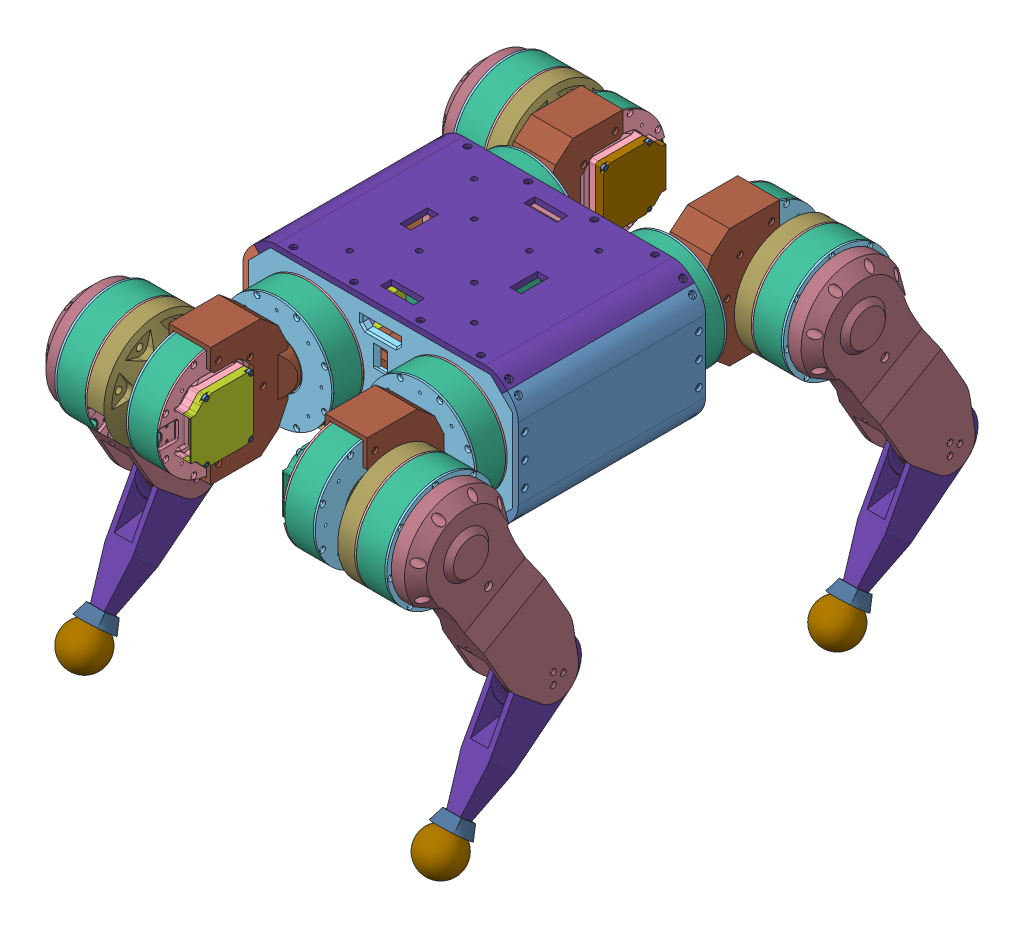
SolidWorks assembly mk2 chassis, configuration Default. Lengths in mm.
Overall size (361.4 327.83 552.81).
210 component instances, 45 part files, 0 mates.
Components (placement in the parent):
- mk2 chassis.stp-1: mk2 chassis.stp [Default] at origin size (361.4 327.83 552.81)
  - mk2 leg.stp-1: mk2 leg.stp [Default] at (-65 0 95) size (165.7 327.83 192.81)
    - qdd100 external.stp-1: qdd100 external.stp [Default] x (0 1 0) z (0 0 1) size (100 100 44.2)
      - Back Cover.stp-1: Back Cover.stp [Default] at origin size (56.5 56.9 10.6)
        - 91292A012.stp-1: 91292A012.stp [Default] at (-26 19 -14.4) size (4.5 4.5 10.5)
        - 91292A012.stp-2: 91292A012.stp [Default] at (26 19 -14.4) size (4.5 4.5 10.5)
        - 91292A012.stp-3: 91292A012.stp [Default] at (26 -21 -14.4) size (4.5 4.5 10.5)
        - 91292A012.stp-4: 91292A012.stp [Default] at (-26 -21 -14.4) size (4.5 4.5 10.5)
        - Back Cover-0.stp-1: Back Cover-0.stp [Default] at origin size (56.5 56.9 7.5)
      - Planet Output.stp-1: Planet Output.stp [Default] at (0 0 12.2) x (0.5 -0.866025 0) z (0 0 1) size (43 43 14.5)
      - Back Housing.stp-1: Back Housing.stp [Default] at (0 0 -1.5) size (100 99.47 11)
      - Front Housing.stp-1: Front Housing.stp [Default] at (0 0 12.2) size (100 100 20.87)
      - Outer Housing.stp-1: Outer Housing.stp [Default] at origin size (100 100 25.8)
    - qdd100 external_1.stp-1: qdd100 external_1.stp [Default] at (-1.5 0 85) x (0 1 0) z (-1 0 0) size (100 100 44.2)
      - Back Cover_1.stp-1: Back Cover_1.stp [Default] at origin size (56.5 56.9 10.6)
        - 91292A012.stp-1: 91292A012.stp [Default] at (-26 19 -14.4) size (4.5 4.5 10.5)
        - 91292A012.stp-2: 91292A012.stp [Default] at (26 19 -14.4) size (4.5 4.5 10.5)
        - 91292A012.stp-3: 91292A012.stp [Default] at (26 -21 -14.4) size (4.5 4.5 10.5)
        - 91292A012.stp-4: 91292A012.stp [Default] at (-26 -21 -14.4) size (4.5 4.5 10.5)
        - Back Cover_1-1.stp-1: Back Cover_1-1.stp [Default] at origin size (56.5 56.9 7.5)
      - Planet Output.stp-1: Planet Output.stp [Default] at (0 0 12.2) size (43 43 14.5)
      - Back Housing.stp-1: Back Housing.stp [Default] at (0 0 -1.5) size (100 99.47 11)
      - Front Housing.stp-1: Front Housing.stp [Default] at (0 0 12.2) size (100 100 20.87)
      - Outer Housing.stp-1: Outer Housing.stp [Default] at origin size (100 100 25.8)
    - qdd100 external_2.stp-1: qdd100 external_2.stp [Default] at (-66.5 0 85) x (0 0.866025 0.5) z (-1 0 0) size (100 100 44.2)
      - Back Cover_2.stp-1: Back Cover_2.stp [Default] at origin size (56.5 56.9 10.6)
        - 91292A012.stp-1: 91292A012.stp [Default] at (-26 19 -14.4) size (4.5 4.5 10.5)
        - 91292A012.stp-2: 91292A012.stp [Default] at (26 19 -14.4) size (4.5 4.5 10.5)
        - 91292A012.stp-3: 91292A012.stp [Default] at (26 -21 -14.4) size (4.5 4.5 10.5)
        - 91292A012.stp-4: 91292A012.stp [Default] at (-26 -21 -14.4) size (4.5 4.5 10.5)
        - Back Cover_2-2.stp-1: Back Cover_2-2.stp [Default] at origin size (56.5 56.9 7.5)
      - Planet Output.stp-1: Planet Output.stp [Default] at (0 0 12.2) size (43 43 14.5)
      - Back Housing.stp-1: Back Housing.stp [Default] at (0 0 -1.5) size (100 99.47 11)
      - Front Housing.stp-1: Front Housing.stp [Default] at (0 0 12.2) size (100 100 20.87)
      - Outer Housing.stp-1: Outer Housing.stp [Default] at origin size (100 100 25.8)
    - Leg.stp-1: Leg.stp [Default] at origin size (137.7 327.83 192.56)
      - Foot.stp-1: Foot.stp [Default] at (0 -69.5691 -150.7891) x (1 0 0) z (0 0.642788 0.766044) size (38 45.01 38)
        - Ball.stp-1: Ball.stp [Default] at (0 -369.35 -177) x (1 0 0) z (0 1 0) size (38 38 38)
        - Foot Bracket.stp-1: Foot Bracket.stp [Default] at origin size (32.62 31.01 32.62)
      - Shoulder.stp-1: Shoulder.stp [Default] at origin size (47 108 73)
      - Upper Motor Joint.stp-1: Upper Motor Joint.stp [Default] at (0 42.5 11.3878) x (1 0 0) z (0 -0.5 0.866025) size (35.8 100 99.71)
      - Upper Leg.stp-1: Upper Leg.stp [Default] at (0 42.5 11.3878) x (1 0 0) z (0 -0.5 0.866025) size (37 215.35 92)
      - Tensioner.stp-1: Tensioner.stp [Default] at (-96.7 -77.8341 57.383) x (1 0 0) z (0 -0.5 0.866025) size (27 10 16)
      - Upper Pulley.stp-1: Upper Pulley.stp [Default] at (0 42.5 11.3878) x (1 0 0) z (0 -0.5 0.866025) size (20.2 27.85 27.54)
      - Upper Pulley Adapter.stp-1: Upper Pulley Adapter.stp [Default] at (0 42.5 11.3878) x (1 0 0) z (0 -0.5 0.866025) size (3 43 43)
      - Lower Leg.stp-1: Lower Leg.stp [Default] at (0 -69.5691 -150.7891) x (1 0 0) z (0 0.642788 0.766044) size (25.02 152.46 56.93)
      - Lower Pulley.stp-1: Lower Pulley.stp [Default] at (0 42.5 11.3878) x (1 0 0) z (0 -0.5 0.866025) size (16 50.03 50.03)
      - Knee Stud.stp-1: Knee Stud.stp [Default] at (0 42.5 11.3878) x (1 0 0) z (0 -0.5 0.866025) size (25 20 20)
  - mk2 leg_1.stp-1: mk2 leg_1.stp [Default] at (65 0 -95) x (-1 0 0) z (0 0 -1) size (165.7 327.83 234.51)
    - qdd100 external_3.stp-1: qdd100 external_3.stp [Default] x (0 1 0) z (0 0 1) size (100 100 44.2)
      - Back Cover_3.stp-1: Back Cover_3.stp [Default] at origin size (56.5 56.9 10.6)
        - 91292A012.stp-1: 91292A012.stp [Default] at (-26 19 -14.4) size (4.5 4.5 10.5)
        - 91292A012.stp-2: 91292A012.stp [Default] at (26 19 -14.4) size (4.5 4.5 10.5)
        - 91292A012.stp-3: 91292A012.stp [Default] at (26 -21 -14.4) size (4.5 4.5 10.5)
        - 91292A012.stp-4: 91292A012.stp [Default] at (-26 -21 -14.4) size (4.5 4.5 10.5)
        - Back Cover_3-3.stp-1: Back Cover_3-3.stp [Default] at origin size (56.5 56.9 7.5)
      - Planet Output.stp-1: Planet Output.stp [Default] at (0 0 12.2) x (0.5 -0.866025 0) z (0 0 1) size (43 43 14.5)
      - Back Housing.stp-1: Back Housing.stp [Default] at (0 0 -1.5) size (100 99.47 11)
      - Front Housing.stp-1: Front Housing.stp [Default] at (0 0 12.2) size (100 100 20.87)
      - Outer Housing.stp-1: Outer Housing.stp [Default] at origin size (100 100 25.8)
    - qdd100 external_4.stp-1: qdd100 external_4.stp [Default] at (-1.5 0 85) x (0 1 0) z (-1 0 0) size (100 100 44.2)
      - Back Cover_4.stp-1: Back Cover_4.stp [Default] at origin size (56.5 56.9 10.6)
        - 91292A012.stp-1: 91292A012.stp [Default] at (-26 19 -14.4) size (4.5 4.5 10.5)
        - 91292A012.stp-2: 91292A012.stp [Default] at (26 19 -14.4) size (4.5 4.5 10.5)
        - 91292A012.stp-3: 91292A012.stp [Default] at (26 -21 -14.4) size (4.5 4.5 10.5)
        - 91292A012.stp-4: 91292A012.stp [Default] at (-26 -21 -14.4) size (4.5 4.5 10.5)
        - Back Cover_4-4.stp-1: Back Cover_4-4.stp [Default] at origin size (56.5 56.9 7.5)
      - Planet Output.stp-1: Planet Output.stp [Default] at (0 0 12.2) size (43 43 14.5)
      - Back Housing.stp-1: Back Housing.stp [Default] at (0 0 -1.5) size (100 99.47 11)
      - Front Housing.stp-1: Front Housing.stp [Default] at (0 0 12.2) size (100 100 20.87)
      - Outer Housing.stp-1: Outer Housing.stp [Default] at origin size (100 100 25.8)
    - qdd100 external_5.stp-1: qdd100 external_5.stp [Default] at (-66.5 0 85) x (0 0.866025 -0.5) z (-1 0 0) size (100 100 44.2)
      - Back Cover_5.stp-1: Back Cover_5.stp [Default] at origin size (56.5 56.9 10.6)
        - 91292A012.stp-1: 91292A012.stp [Default] at (-26 19 -14.4) size (4.5 4.5 10.5)
        - 91292A012.stp-2: 91292A012.stp [Default] at (26 19 -14.4) size (4.5 4.5 10.5)
        - 91292A012.stp-3: 91292A012.stp [Default] at (26 -21 -14.4) size (4.5 4.5 10.5)
        - 91292A012.stp-4: 91292A012.stp [Default] at (-26 -21 -14.4) size (4.5 4.5 10.5)
        - Back Cover_5-5.stp-1: Back Cover_5-5.stp [Default] at origin size (56.5 56.9 7.5)
      - Planet Output.stp-1: Planet Output.stp [Default] at (0 0 12.2) size (43 43 14.5)
      - Back Housing.stp-1: Back Housing.stp [Default] at (0 0 -1.5) size (100 99.47 11)
      - Front Housing.stp-1: Front Housing.stp [Default] at (0 0 12.2) size (100 100 20.87)
      - Outer Housing.stp-1: Outer Housing.stp [Default] at origin size (100 100 25.8)
    - Leg_1.stp-1: Leg_1.stp [Default] at origin size (137.7 327.68 192.81)
      - Foot_1.stp-1: Foot_1.stp [Default] at (0 39.7048 190.5616) x (1 0 0) z (0 -0.642788 0.766044) size (38 45.01 38)
        - Ball.stp-1: Ball.stp [Default] at (0 -369.35 -177) x (1 0 0) z (0 1 0) size (38 38 38)
        - Foot Bracket.stp-1: Foot Bracket.stp [Default] at origin size (32.62 31.01 32.62)
      - Shoulder.stp-1: Shoulder.stp [Default] at origin size (47 108 73)
      - Upper Motor Joint.stp-1: Upper Motor Joint.stp [Default] at (0 -42.5 11.3878) x (1 0 0) z (0 0.5 0.866025) size (35.8 100 99.71)
      - Upper Leg.stp-1: Upper Leg.stp [Default] at (0 -42.5 11.3878) x (1 0 0) z (0 0.5 0.866025) size (37 215.35 92)
      - Tensioner.stp-1: Tensioner.stp [Default] at (-96.7 -62.8341 138.5978) x (1 0 0) z (0 0.5 0.866025) size (27 10 16)
      - Upper Pulley.stp-1: Upper Pulley.stp [Default] at (0 -42.5 11.3878) x (1 0 0) z (0 0.5 0.866025) size (20.2 27.85 27.54)
      - Upper Pulley Adapter.stp-1: Upper Pulley Adapter.stp [Default] at (0 -42.5 11.3878) x (1 0 0) z (0 0.5 0.866025) size (3 43 43)
      - Lower Leg.stp-1: Lower Leg.stp [Default] at (0 39.7048 190.5616) x (1 0 0) z (0 -0.642788 0.766044) size (25.02 152.46 56.93)
      - Lower Pulley.stp-1: Lower Pulley.stp [Default] at (0 -42.5 11.3878) x (1 0 0) z (0 0.5 0.866025) size (16 50.03 50.03)
      - Knee Stud.stp-1: Knee Stud.stp [Default] at (0 -42.5 11.3878) x (1 0 0) z (0 0.5 0.866025) size (25 20 20)
  - mk2 leg_2.stp-1: mk2 leg_2.stp [Default] at (65 0 95) x (-1 0 0) z (0 0 1) size (165.7 327.83 192.81)
    - qdd100 external_6.stp-1: qdd100 external_6.stp [Default] x (0 1 0) z (0 0 1) size (100 100 44.2)
      - Back Cover_6.stp-1: Back Cover_6.stp [Default] at origin size (56.5 56.9 10.6)
        - 91292A012.stp-1: 91292A012.stp [Default] at (-26 19 -14.4) size (4.5 4.5 10.5)
        - 91292A012.stp-2: 91292A012.stp [Default] at (26 19 -14.4) size (4.5 4.5 10.5)
        - 91292A012.stp-3: 91292A012.stp [Default] at (26 -21 -14.4) size (4.5 4.5 10.5)
        - 91292A012.stp-4: 91292A012.stp [Default] at (-26 -21 -14.4) size (4.5 4.5 10.5)
        - Back Cover_6-6.stp-1: Back Cover_6-6.stp [Default] at origin size (56.5 56.9 7.5)
      - Planet Output.stp-1: Planet Output.stp [Default] at (0 0 12.2) x (0.5 -0.866025 0) z (0 0 1) size (43 43 14.5)
      - Back Housing.stp-1: Back Housing.stp [Default] at (0 0 -1.5) size (100 99.47 11)
      - Front Housing.stp-1: Front Housing.stp [Default] at (0 0 12.2) size (100 100 20.87)
      - Outer Housing.stp-1: Outer Housing.stp [Default] at origin size (100 100 25.8)
    - qdd100 external_7.stp-1: qdd100 external_7.stp [Default] at (-1.5 0 85) x (0 1 0) z (-1 0 0) size (100 100 44.2)
      - Back Cover_7.stp-1: Back Cover_7.stp [Default] at origin size (56.5 56.9 10.6)
        - 91292A012.stp-1: 91292A012.stp [Default] at (-26 19 -14.4) size (4.5 4.5 10.5)
        - 91292A012.stp-2: 91292A012.stp [Default] at (26 19 -14.4) size (4.5 4.5 10.5)
        - 91292A012.stp-3: 91292A012.stp [Default] at (26 -21 -14.4) size (4.5 4.5 10.5)
        - 91292A012.stp-4: 91292A012.stp [Default] at (-26 -21 -14.4) size (4.5 4.5 10.5)
        - Back Cover_7-7.stp-1: Back Cover_7-7.stp [Default] at origin size (56.5 56.9 7.5)
      - Planet Output.stp-1: Planet Output.stp [Default] at (0 0 12.2) size (43 43 14.5)
      - Back Housing.stp-1: Back Housing.stp [Default] at (0 0 -1.5) size (100 99.47 11)
      - Front Housing.stp-1: Front Housing.stp [Default] at (0 0 12.2) size (100 100 20.87)
      - Outer Housing.stp-1: Outer Housing.stp [Default] at origin size (100 100 25.8)
    - qdd100 external_8.stp-1: qdd100 external_8.stp [Default] at (-66.5 0 85) x (0 -0.866025 0.5) z (-1 0 0) size (100 100 44.2)
      - Back Cover_8.stp-1: Back Cover_8.stp [Default] at origin size (56.5 56.9 10.6)
        - 91292A012.stp-1: 91292A012.stp [Default] at (-26 19 -14.4) size (4.5 4.5 10.5)
        - 91292A012.stp-2: 91292A012.stp [Default] at (26 19 -14.4) size (4.5 4.5 10.5)
        - 91292A012.stp-3: 91292A012.stp [Default] at (26 -21 -14.4) size (4.5 4.5 10.5)
        - 91292A012.stp-4: 91292A012.stp [Default] at (-26 -21 -14.4) size (4.5 4.5 10.5)
        - Back Cover_8-8.stp-1: Back Cover_8-8.stp [Default] at origin size (56.5 56.9 7.5)
      - Planet Output.stp-1: Planet Output.stp [Default] at (0 0 12.2) size (43 43 14.5)
      - Back Housing.stp-1: Back Housing.stp [Default] at (0 0 -1.5) size (100 99.47 11)
      - Front Housing.stp-1: Front Housing.stp [Default] at (0 0 12.2) size (100 100 20.87)
      - Outer Housing.stp-1: Outer Housing.stp [Default] at origin size (100 100 25.8)
    - Leg_2.stp-1: Leg_2.stp [Default] at origin size (137.7 327.68 192.81)
      - Foot_2.stp-1: Foot_2.stp [Default] at (0 -39.7048 -20.5616) x (1 0 0) z (0 0.642788 -0.766044) size (38 45.01 38)
        - Ball.stp-1: Ball.stp [Default] at (0 -369.35 -177) x (1 0 0) z (0 1 0) size (38 38 38)
        - Foot Bracket.stp-1: Foot Bracket.stp [Default] at origin size (32.62 31.01 32.62)
      - Shoulder.stp-1: Shoulder.stp [Default] at origin size (47 108 73)
      - Upper Motor Joint.stp-1: Upper Motor Joint.stp [Default] at (0 42.5 158.6122) x (1 0 0) z (0 -0.5 -0.866025) size (35.8 100 99.71)
      - Upper Leg.stp-1: Upper Leg.stp [Default] at (0 42.5 158.6122) x (1 0 0) z (0 -0.5 -0.866025) size (37 215.35 92)
      - Tensioner.stp-1: Tensioner.stp [Default] at (-96.7 62.8341 31.4022) x (1 0 0) z (0 -0.5 -0.866025) size (27 10 16)
      - Upper Pulley.stp-1: Upper Pulley.stp [Default] at (0 42.5 158.6122) x (1 0 0) z (0 -0.5 -0.866025) size (20.2 27.85 27.54)
      - Upper Pulley Adapter.stp-1: Upper Pulley Adapter.stp [Default] at (0 42.5 158.6122) x (1 0 0) z (0 -0.5 -0.866025) size (3 43 43)
      - Lower Leg.stp-1: Lower Leg.stp [Default] at (0 -39.7048 -20.5616) x (1 0 0) z (0 0.642788 -0.766044) size (25.02 152.46 56.93)
      - Lower Pulley.stp-1: Lower Pulley.stp [Default] at (0 42.5 158.6122) x (1 0 0) z (0 -0.5 -0.866025) size (16 50.03 50.03)
      - Knee Stud.stp-1: Knee Stud.stp [Default] at (0 42.5 158.6122) x (1 0 0) z (0 -0.5 -0.866025) size (25 20 20)
  - mk2 leg_3.stp-1: mk2 leg_3.stp [Default] at (-65 0 -95) x (1 0 0) z (0 0 -1) size (165.7 327.83 234.51)
    - qdd100 external_9.stp-1: qdd100 external_9.stp [Default] x (0 1 0) z (0 0 1) size (100 100 44.2)
      - Back Cover_9.stp-1: Back Cover_9.stp [Default] at origin size (56.5 56.9 10.6)
        - 91292A012.stp-1: 91292A012.stp [Default] at (-26 19 -14.4) size (4.5 4.5 10.5)
        - 91292A012.stp-2: 91292A012.stp [Default] at (26 19 -14.4) size (4.5 4.5 10.5)
        - 91292A012.stp-3: 91292A012.stp [Default] at (26 -21 -14.4) size (4.5 4.5 10.5)
        - 91292A012.stp-4: 91292A012.stp [Default] at (-26 -21 -14.4) size (4.5 4.5 10.5)
        - Back Cover_9-9.stp-1: Back Cover_9-9.stp [Default] at origin size (56.5 56.9 7.5)
      - Planet Output.stp-1: Planet Output.stp [Default] at (0 0 12.2) x (0.5 -0.866025 0) z (0 0 1) size (43 43 14.5)
      - Back Housing.stp-1: Back Housing.stp [Default] at (0 0 -1.5) size (100 99.47 11)
      - Front Housing.stp-1: Front Housing.stp [Default] at (0 0 12.2) size (100 100 20.87)
      - Outer Housing.stp-1: Outer Housing.stp [Default] at origin size (100 100 25.8)
    - qdd100 external_10.stp-1: qdd100 external_10.stp [Default] at (-1.5 0 85) x (0 1 0) z (-1 0 0) size (100 100 44.2)
      - Back Cover_10.stp-1: Back Cover_10.stp [Default] at origin size (56.5 56.9 10.6)
        - 91292A012.stp-1: 91292A012.stp [Default] at (-26 19 -14.4) size (4.5 4.5 10.5)
        - 91292A012.stp-2: 91292A012.stp [Default] at (26 19 -14.4) size (4.5 4.5 10.5)
        - 91292A012.stp-3: 91292A012.stp [Default] at (26 -21 -14.4) size (4.5 4.5 10.5)
        - 91292A012.stp-4: 91292A012.stp [Default] at (-26 -21 -14.4) size (4.5 4.5 10.5)
        - Back Cover_10-10.stp-1: Back Cover_10-10.stp [Default] at origin size (56.5 56.9 7.5)
      - Planet Output.stp-1: Planet Output.stp [Default] at (0 0 12.2) size (43 43 14.5)
      - Back Housing.stp-1: Back Housing.stp [Default] at (0 0 -1.5) size (100 99.47 11)
      - Front Housing.stp-1: Front Housing.stp [Default] at (0 0 12.2) size (100 100 20.87)
      - Outer Housing.stp-1: Outer Housing.stp [Default] at origin size (100 100 25.8)
    - qdd100 external_11.stp-1: qdd100 external_11.stp [Default] at (-66.5 0 85) x (0 -0.866025 -0.5) z (-1 0 0) size (100 100 44.2)
      - Back Cover_11.stp-1: Back Cover_11.stp [Default] at origin size (56.5 56.9 10.6)
        - 91292A012.stp-1: 91292A012.stp [Default] at (-26 19 -14.4) size (4.5 4.5 10.5)
        - 91292A012.stp-2: 91292A012.stp [Default] at (26 19 -14.4) size (4.5 4.5 10.5)
        - 91292A012.stp-3: 91292A012.stp [Default] at (26 -21 -14.4) size (4.5 4.5 10.5)
        - 91292A012.stp-4: 91292A012.stp [Default] at (-26 -21 -14.4) size (4.5 4.5 10.5)
        - Back Cover_11-11.stp-1: Back Cover_11-11.stp [Default] at origin size (56.5 56.9 7.5)
      - Planet Output.stp-1: Planet Output.stp [Default] at (0 0 12.2) size (43 43 14.5)
      - Back Housing.stp-1: Back Housing.stp [Default] at (0 0 -1.5) size (100 99.47 11)
      - Front Housing.stp-1: Front Housing.stp [Default] at (0 0 12.2) size (100 100 20.87)
      - Outer Housing.stp-1: Outer Housing.stp [Default] at origin size (100 100 25.8)
    - Leg_3.stp-1: Leg_3.stp [Default] at origin size (137.7 327.83 192.56)
      - Foot_3.stp-1: Foot_3.stp [Default] at (0 69.5691 320.7891) x (1 0 0) z (0 -0.642788 -0.766044) size (38 45.01 38)
        - Ball.stp-1: Ball.stp [Default] at (0 -369.35 -177) x (1 0 0) z (0 1 0) size (38 38 38)
        - Foot Bracket.stp-1: Foot Bracket.stp [Default] at origin size (32.62 31.01 32.62)
      - Shoulder.stp-1: Shoulder.stp [Default] at origin size (47 108 73)
      - Upper Motor Joint.stp-1: Upper Motor Joint.stp [Default] at (0 -42.5 158.6122) x (1 0 0) z (0 0.5 -0.866025) size (35.8 100 99.71)
      - Upper Leg.stp-1: Upper Leg.stp [Default] at (0 -42.5 158.6122) x (1 0 0) z (0 0.5 -0.866025) size (37 215.35 92)
      - Tensioner.stp-1: Tensioner.stp [Default] at (-96.7 77.8341 112.617) x (1 0 0) z (0 0.5 -0.866025) size (27 10 16)
      - Upper Pulley.stp-1: Upper Pulley.stp [Default] at (0 -42.5 158.6122) x (1 0 0) z (0 0.5 -0.866025) size (20.2 27.85 27.54)
      - Upper Pulley Adapter.stp-1: Upper Pulley Adapter.stp [Default] at (0 -42.5 158.6122) x (1 0 0) z (0 0.5 -0.866025) size (3 43 43)
      - Lower Leg.stp-1: Lower Leg.stp [Default] at (0 69.5691 320.7891) x (1 0 0) z (0 -0.642788 -0.766044) size (25.02 152.46 56.93)
      - Lower Pulley.stp-1: Lower Pulley.stp [Default] at (0 -42.5 158.6122) x (1 0 0) z (0 0.5 -0.866025) size (16 50.03 50.03)
      - Knee Stud.stp-1: Knee Stud.stp [Default] at (0 -42.5 158.6122) x (1 0 0) z (0 0.5 -0.866025) size (25 20 20)
  - ONEplus Battery.stp-1: ONEplus Battery.stp [Default] at (0 10 15) size (82 106 135.5)
    - Battery.stp-1: Battery.stp [Default] at (0 2.5 -1) size (82 106 135.5)
  - pi3hat.stp-1: pi3hat.stp [Default] x (0 1 0) z (0 0 1) size (74.02 32.03 106.9)
    - pi3bplus.stp-1: pi3bplus.stp [Default] at (57 -7.9746 112) x (1 0 0) z (0 0 -1) size (58.47 17.52 87.03)
    - pi3hat_1.stp-1: pi3hat_1.stp [Default] at (0.25 -97.5014 10) size (67.4 17.6 65)
    - RF Support.stp-1: RF Support.stp [Default] at (1 -109.4774 3) size (8 10.87 27)
    - RF Clamp.stp-1: RF Clamp.stp [Default] at (1 -109.4774 3) size (8 6.16 27)
    - Antenna.stp-1: Antenna.stp [Default] at (-63.826 -104.8514 63.2) x (0 0 1) z (0 1 0) size (87.7 9.3 9.3)
  - Chassis.stp-1: Chassis.stp [Default] at origin size (250 125 170)
    - Body.stp-1: Body.stp [Default] at origin size (250 125 170)
      - Top.stp-1: Top.stp [Default] at origin size (230.1 15 170)
      - Bottom.stp-1: Bottom.stp [Default] at origin size (95.05 15 170)
      - Left.stp-1: Left.stp [Default] at origin size (15 105.1 170)
      - Right.stp-1: Right.stp [Default] at origin size (15 105.1 170)
      - Bottom Right.stp-1: Bottom Right.stp [Default] at origin size (95.05 15 170)
    - Front Plate.stp-1: Front Plate.stp [Default] at origin size (240 115 21)
    - Front Plate(Mirror).stp-1: Front Plate(Mirror).stp [Default] at origin size (240 115 21)
    - Battery Stud Mount.stp-1: Battery Stud Mount.stp [Default] at (0 12.5 -1) size (86 54 84)
    - Stiffener.stp-1: Stiffener.stp [Default] at origin size (101.8 82.06 145)
    - Internal Cover.stp-1: Internal Cover.stp [Default] at origin size (140 60.5 150)
  - Power Distribution Board.stp-1: Power Distribution Board.stp [Default] at (-115 0 0) x (0 0 -1) z (0 -1 0) size (70 12.5 45)
